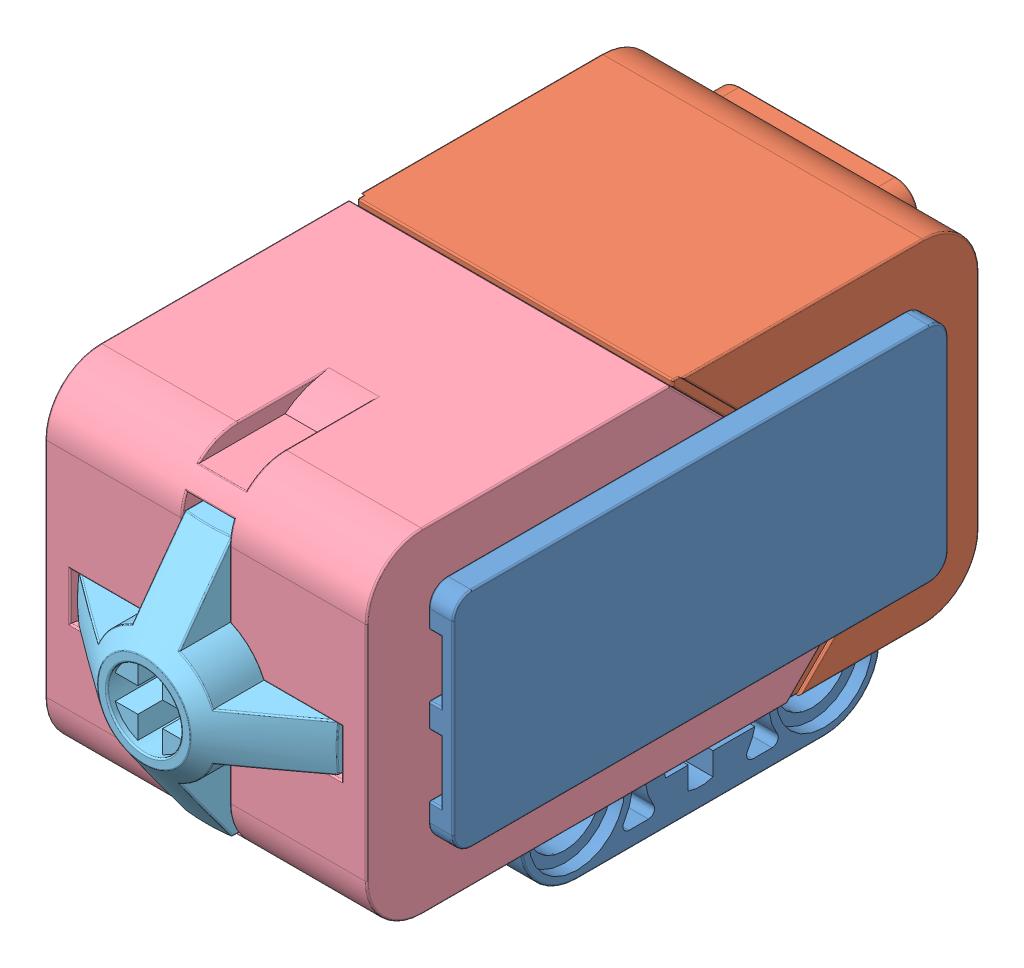
SolidWorks assembly LEGOEV3TOUCHSENSOR, configuration Default. Lengths in mm.
Overall size (24 31.05 43.62).
7 component instances, 5 part files, 0 mates.
Components (placement in the parent):
- 95648.stp-1: 95648.stp [Default] at origin size (24 31.05 43.62)
  - 99385c01.stp-1: 99385c01.stp [Default] at origin size (24 31.05 39.62)
    - 99377-LtBluishGray.stp-1: 99377-LtBluishGray.stp [Default] at origin size (24 29.6 38)
    - 99376-White.stp-1: 99376-White.stp [Default] at (0 0.44 -14.2) size (22.3 23.6 19.62)
    - 54732b-LtBluishGray.stp-1: 54732b-LtBluishGray.stp [Default] at (0 2.04 -20.2) x (-1 0 0) z (0 0 -1) size (12 14.56 14.4)
    - 99385-LtBluishGray.stp-1: 99385-LtBluishGray.stp [Default] at (0 0.44 13.8) size (22.4 21.61 30.66)
  - 99386-Red.stp-1: 99386-Red.stp [Default] at (0 -0.36 15.4) size (18.23 16.99 14.8)
